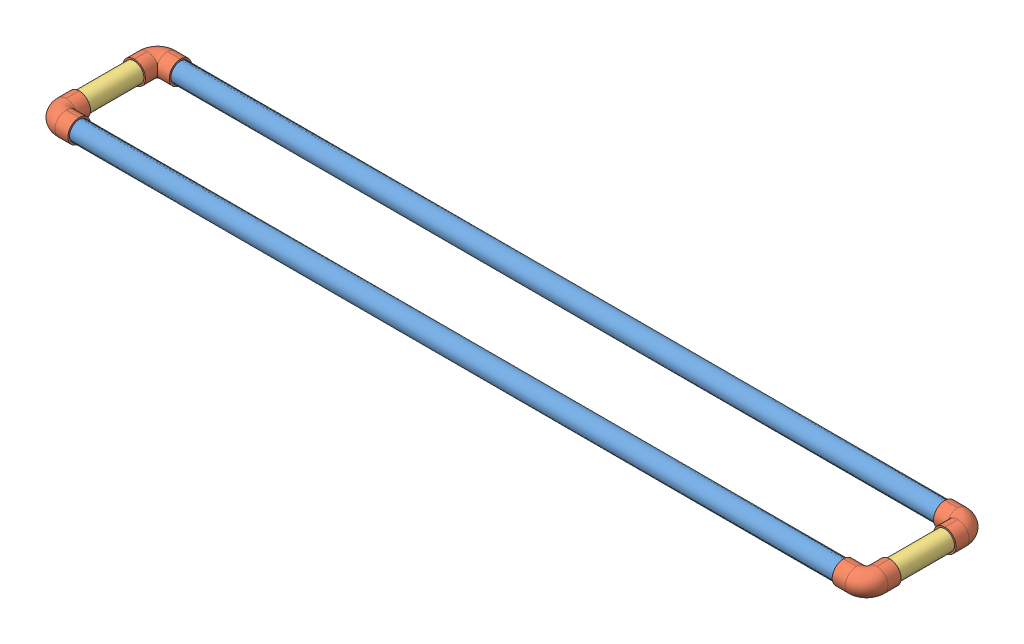
SolidWorks assembly GE-19183, configuration Default. Lengths in mm.
Overall size (2096.88 66.73 317.03).
8 component instances, 3 part files, 20 mates.
Components (placement in the parent):
- GE-19183-01-1: GE-19183-01 [Default] at (1403.4262 -24.13 58.039) x (1 0 0) z (0 0.381849 0.924225) size (1981.2 48.26 48.26)
- GE-19184-1: GE-19184 [Default] at (3410.0262 -24.13 58.039) x (1 0 0) z (0 1 0) size (86.36 86.36 56.64)
- GE-19184-2: GE-19184 [Default] at (1378.0262 -24.13 58.039) x (-1 0 0) z (0 -1 0) size (86.36 86.36 56.64)
- GE-19183-02-1: GE-19183-02 [Default] at (1378.0262 -24.13 32.639) x (0 0 -1) z (-0.543004 -0.83973 0) size (203.2 48.26 48.26)
- GE-19183-02-2: GE-19183-02 [Default] at (3410.0262 -24.13 32.639) x (0 0 -1) z (0.924225 0.381849 0) size (203.2 48.26 48.26)
- GE-19184-3: GE-19184 [Default] at (1378.0262 -24.13 -195.961) x (-1 0 0) z (0 1 0) size (86.36 86.36 56.64)
- GE-19184-4: GE-19184 [Default] at (3410.0262 -24.13 -195.961) x (1 0 0) z (0 -1 0) size (86.36 86.36 56.64)
- GE-19183-01-2: GE-19183-01 [Default] at (1403.4262 -24.13 -195.961) x (1 0 0) z (0 -0.381849 -0.924225) size (1981.2 48.26 48.26)
Mates (geometry in assembly coordinates):
- Coincident6: coincident: plane of GE-19183-01-1 through (1403.4262 -24.13 58.039) normal (-1 0 0); plane of GE-19184-2 through (1403.4262 -24.13 58.039) normal (1 0 0)
- Concentric4: concentric: cylinder of GE-19183-01-1 through (3384.6262 -24.13 58.039) axis (-1 0 0) radius 24.13; cylinder of GE-19184-2 through (1403.4262 -24.13 58.039) axis (-1 0 0) radius 7.0038
- Concentric5: concentric: cylinder of GE-19183-01-1 through (3384.6262 -24.13 58.039) axis (-1 0 0) radius 24.13; cylinder of GE-19184-1 through (3384.6262 -24.13 58.039) axis (1 0 0) radius 7.0038
- Coincident8: coincident: plane of assembly; plane of assembly; plane of GE-19184-1 through (3438.3472 -24.13 0) normal (0 0 -1); plane of GE-19184-2 through (1349.7052 -24.13 0) normal (0 0 -1)
- Concentric6: concentric: cone of assembly; cylinder of assembly; cone of GE-19184-1 through (3410.0262 -24.13 0) axis (0 0 1); cylinder of GE-19183-02-2 through (3410.0262 -24.13 -170.561) axis (0 0 1) radius 24.13
- Coincident9: coincident: plane of assembly; plane of assembly; plane of GE-19184-1 through (3410.0262 -24.13 32.639) normal (0 0 -1); plane of GE-19183-02-2 through (3410.0262 -24.13 32.639) normal (0 0 1)
- Concentric7: concentric: cone of assembly; cylinder of assembly; cone of GE-19184-2 through (1378.0262 -24.13 0) axis (0 0 1); cylinder of GE-19183-02-1 through (1378.0262 -24.13 -170.561) axis (0 0 1) radius 24.13
- Coincident10: coincident: plane of assembly; plane of assembly; plane of GE-19184-2 through (1378.0262 -24.13 32.639) normal (0 0 -1); plane of GE-19183-02-1 through (1378.0262 -24.13 32.639) normal (0 0 1)
- Coincident11: coincident: plane of assembly; plane of assembly; plane of GE-19184-3 through (1403.4262 -24.13 -195.961) normal (1 0 0); plane of GE-19183-01-2 through (1403.4262 -24.13 -195.961) normal (-1 0 0)
- Coincident12: coincident: plane of assembly; plane of assembly; plane of GE-19184-4 through (3384.6262 -24.13 -195.961) normal (-1 0 0); plane of GE-19183-01-2 through (3384.6262 -24.13 -195.961) normal (1 0 0)
- Coincident13: coincident: plane of assembly; plane of assembly; plane of GE-19184-3 through (1349.7052 -24.13 -137.922) normal (0 0 1); plane of GE-19184-4 through (3438.3472 -24.13 -137.922) normal (0 0 1)
- Concentric8: concentric: cone of assembly; cylinder of assembly; cone of GE-19184-4 through (3384.6262 -24.13 -195.961) axis (1 0 0); cylinder of GE-19183-01-2 through (3384.6262 -24.13 -195.961) axis (-1 0 0) radius 24.13
- Concentric9: concentric: cone of assembly; cylinder of assembly; cone of GE-19184-3 through (1403.4262 -24.13 -195.961) axis (-1 0 0); cylinder of GE-19183-01-2 through (3384.6262 -24.13 -195.961) axis (-1 0 0) radius 24.13
- Concentric10: concentric: cylinder of assembly; cone of assembly; cylinder of GE-19183-02-2 through (3410.0262 -24.13 -170.561) axis (0 0 1) radius 24.13; cone of GE-19184-4 through (3410.0262 -24.13 -137.922) axis (0 0 -1)
- Coincident14: coincident: plane of assembly; plane of assembly; plane of GE-19183-02-2 through (3410.0262 -24.13 -170.561) normal (0 0 -1); plane of GE-19184-4 through (3410.0262 -24.13 -170.561) normal (0 0 1)
- Concentric11: concentric: cylinder of assembly; cone of assembly; cylinder of GE-19183-02-1 through (1378.0262 -24.13 -170.561) axis (0 0 1) radius 24.13; cone of GE-19184-3 through (1378.0262 -24.13 -137.922) axis (0 0 -1)
- Lock1: lock: unknown of GE-19184-1; unknown of GE-19183-02-2
- Concentric13: concentric: cylinder of assembly; cylinder of assembly; cylinder of GE-19184-2 through (1378.0262 -24.13 58.039) axis (0 0 1) radius 28.321; cylinder of GE-19183-02-1 through (1378.0262 -24.13 -170.561) axis (0 0 1) radius 24.13
- Tangent3: tangent: cylinder of GE-19183-01-1 through (3384.6262 -24.13 58.039) axis (-1 0 0) radius 24.13; plane of assembly through (0 0 0) normal (0 1 0)
- Coincident15: coincident: plane of assembly through (0 0 0) normal (0 0 1); plane of GE-19184-2 through (1349.7052 -24.13 0) normal (0 0 -1); plane of assembly
